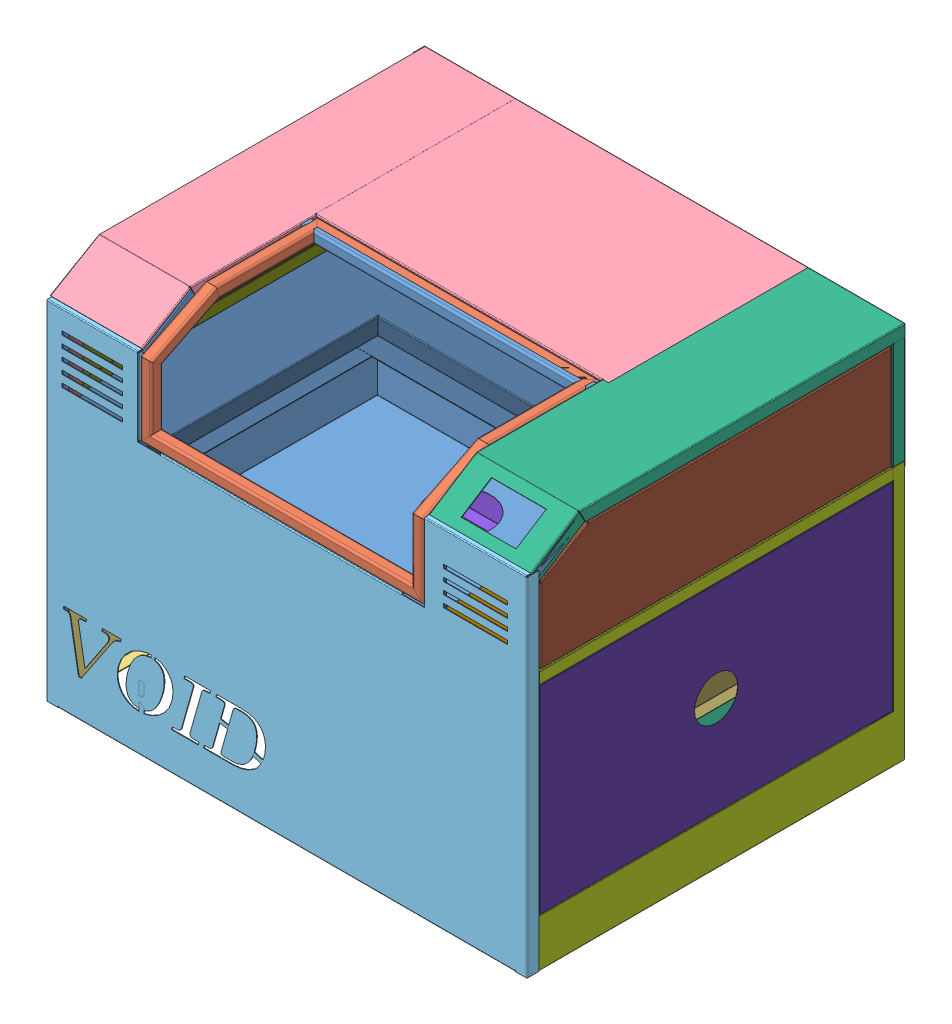
SolidWorks assembly Assem2222, configuration Default. Lengths in mm.
Overall size (1273.78 1001.74 1003.47).
19 component instances, 19 part files, 54 mates.
Components (placement in the parent):
- fram laser1-1: fram laser1 [Default<As Machined>] at (760.0871 624.0307 1171.9426) size (1270 1000 1000)
- door laser2-1: door laser2 [Default<As Machined>] at (485.0871 1026.2791 1646.4121) x (0 0 -1) z (1 0 0) size (469.25 283 750)
- left side-1: left side [Default] at (-496.6495 621.9791 1182.8381) x (-1 0 0) z (0 0 -1) size (33.67 1001.7 1000)
- top laft-1: top laft [Default] at (-361.5167 1123.0157 1366.189) x (0 0 1) z (-1 0 0) size (994.1 108.19 1015)
- Front-1: Front [Default] at (57.9882 671.4556 1683.7747) size (1271.74 921.74 63.67)
- top right-1: top right [Default] at (589.4697 1123.0157 1274.7007) size (303.67 330 991.42)
- right bottom-1: right bottom [Default] at (775.8237 175.3657 1106.8981) size (31.67 686.47 970.04)
- back-1: back [Default] at (140.3562 470.6811 681.3015) x (-1 0 0) z (0 0 -1) size (1270 968.4 31.67)
- bottom right-1: bottom right [Default] at (640.3581 808.0157 1182.5381) size (291.44 45.47 959)
- bottom laft-1: bottom laft [Default] at (276.9901 808.0157 949.0015) size (994 45.47 959)
- door right top-1: door right top [Default] at (776.8237 962.1398 1135.8944) size (30.3 274.04 929.65)
- control hoder-1: control hoder [Default] at (506.8237 511.2791 1182.0381) size (30 528 939.17)
- laft stand door-1: laft stand door [Default] at (-496.6495 923.3416 1667.1542) x (-1 0 0) z (0 0 -1) size (33.67 234 62.15)
- right door stand-1: right door stand [Default] at (-496.6495 1091.0791 1087.153) x (-1 0 0) z (0 0 -1) size (33.84 118 961.37)
- bottom2 right-1: bottom2 right [Default] at (645.0871 248.0157 1212.0381) size (249.7 1.74 979)
- door laft-1: door laft [Default] at (-494.9129 961.2458 1135.881) size (30.15 273.74 929.5)
- door right bottom-1: door right bottom [Default] at (775.8237 511.9157 1181.4381) size (30 526.4 935.9)
- door back-1: door back [Default] at (19.1371 948.8791 681.3015) x (-1 0 0) z (0 0 -1) size (965 279 30)
- smok collection-1: smok collection [Default] at (125.0871 627.0157 1350.7564) size (818.53 150 663.53)
Mates (geometry in assembly coordinates):
- Coincident1: coincident aligned: plane of fram laser1-1 through (-269.9129 1121.2791 1246.8381) normal (0 1 0); plane of door laser2-1 through (485.0871 1121.2791 1237.5929) normal (0 1 0)
- Coincident2: coincident aligned: plane of fram laser1-1 through (-269.9129 801.0791 1682.0381) normal (0 0 1); plane of door laser2-1 through (485.0871 863.0791 1682.0381) normal (0 0 1)
- Width1: width anti-aligned: plane of door laser2-1 through (500.0871 1096.4791 1505.7929) normal (1 0 0); plane of door laser2-1 through (-249.9129 1116.0791 1505.7929) normal (-1 0 0); plane of fram laser1-1 through (-254.9129 1116.0791 1547.0381) normal (1 0 0); plane of fram laser1-1 through (505.0871 1096.4791 1547.0381) normal (-1 0 0)
- Coincident8: coincident anti-aligned: plane of fram laser1-1 through (-479.9129 1096.4791 682.0381) normal (0 0 -1); plane of top laft-1 through (-361.5167 1123.0157 682.0381) normal (0 0 1)
- Coincident12: coincident aligned: plane of fram laser1-1 through (-470.1129 121.2791 706.8381) normal (0 -1 0); plane of left side-1 through (-496.6495 121.2791 1182.8381) normal (0 -1 0)
- Coincident13: coincident anti-aligned: plane of fram laser1-1 through (-269.9129 801.0791 1682.0381) normal (0 0 1); plane of Front-1 through (57.9882 671.4556 1682.0381) normal (0 0 -1)
- Coincident14: coincident anti-aligned: plane of fram laser1-1 through (520.0871 1041.2791 1676.8381) normal (0 1 0); plane of Front-1 through (57.9882 1041.2791 1683.7747) normal (0 -1 0)
- Coincident15: coincident anti-aligned: plane of fram laser1-1 through (775.0871 121.2791 1657.2381) normal (1 0 0); plane of Front-1 through (775.0871 671.4556 1683.7747) normal (-1 0 0)
- Coincident17: coincident anti-aligned: plane of top laft-1 through (520.0871 1121.2791 1210.7881) normal (1 0 0); plane of top right-1 through (520.0871 1121.2791 1210.7881) normal (-1 0 0)
- Coincident18: coincident anti-aligned: plane of fram laser1-1 through (750.2871 1106.2791 682.0381) normal (0 0 -1); plane of top right-1 through (589.4697 1123.0157 682.0381) normal (0 0 1)
- Coincident19: coincident anti-aligned: plane of fram laser1-1 through (-494.9129 121.2791 1676.8381) normal (-1 0 0); plane of left side-1 through (-494.9129 621.9791 1182.8381) normal (1 0 0)
- Coincident20: coincident anti-aligned: plane of fram laser1-1 through (-479.9129 1121.2791 706.8381) normal (0 1 0); plane of top right-1 through (589.4697 1121.2791 1274.7007) normal (0 -1 0)
- Coincident21: coincident anti-aligned: plane of fram laser1-1 through (775.0871 801.0791 1667.0381) normal (1 0 0); plane of right bottom-1 through (775.0871 175.3657 1106.8981) normal (-1 0 0)
- Coincident22: coincident aligned: plane of fram laser1-1 through (750.2871 1106.2791 682.0381) normal (0 0 -1); plane of right bottom-1 through (775.0871 122.0157 682.0381) normal (0 0 -1)
- Coincident23: coincident aligned: plane of fram laser1-1 through (769.8871 121.2791 706.8381) normal (0 -1 0); plane of right bottom-1 through (775.8237 121.2791 1106.8981) normal (0 -1 0)
- Coincident25: coincident anti-aligned: plane of fram laser1-1 through (-489.7129 1106.2791 682.0381) normal (0 0 -1); plane of back-1 through (140.3562 470.6811 682.0381) normal (0 0 1)
- Coincident26: coincident anti-aligned: plane of top right-1 through (525.0871 1121.2791 680.3015) normal (-1 0 0); plane of back-1 through (525.0871 792.6791 682.0381) normal (1 0 0)
- Coincident27: coincident anti-aligned: plane of fram laser1-1 through (529.8871 806.2791 1667.0381) normal (0 1 0); plane of bottom right-1 through (640.3581 806.2791 1182.5381) normal (0 -1 0)
- Coincident28: coincident anti-aligned: plane of fram laser1-1 through (529.8871 791.2791 1652.0381) normal (0 0 -1); plane of bottom right-1 through (520.0871 806.2791 1652.0381) normal (0 0 1)
- Coincident29: coincident anti-aligned: plane of fram laser1-1 through (505.0871 781.4791 1667.0381) normal (-1 0 0); plane of bottom right-1 through (505.0871 808.0157 1182.5381) normal (1 0 0)
- Coincident30: coincident anti-aligned: plane of fram laser1-1 through (-260.1129 791.2791 1652.0381) normal (0 0 -1); plane of bottom laft-1 through (-254.9129 806.2791 1652.0381) normal (0 0 1)
- Coincident31: coincident anti-aligned: plane of fram laser1-1 through (-260.1129 806.2791 1667.0381) normal (0 1 0); plane of bottom laft-1 through (276.9901 806.2791 949.0015) normal (0 -1 0)
- Coincident32: coincident anti-aligned: plane of fram laser1-1 through (-254.9129 801.0791 1667.0381) normal (1 0 0); plane of bottom laft-1 through (-254.9129 808.0157 949.0015) normal (-1 0 0)
- Coincident36: coincident anti-aligned: plane of fram laser1-1 through (-494.9129 121.2791 1676.8381) normal (-1 0 0); plane of laft stand door-1 through (-494.9129 923.3416 1667.1542) normal (1 0 0)
- Coincident37: coincident anti-aligned: plane of fram laser1-1 through (-470.1129 121.2791 1652.0381) normal (0 0 -1); plane of laft stand door-1 through (-496.6495 923.3416 1652.0381) normal (0 0 1)
- Coincident38: coincident anti-aligned: plane of left side-1 through (-494.9129 806.2791 711.9381) normal (0 1 0); plane of laft stand door-1 through (-494.9129 806.2791 1652.0381) normal (0 -1 0)
- Coincident40: coincident anti-aligned: plane of left side-1 through (-494.9129 1122.9791 711.9381) normal (0 0 1); plane of right door stand-1 through (-462.9763 1087.3425 711.9381) normal (0 0 -1)
- Coincident41: coincident: line of top laft-1 through (-494.9129 1121.2791 682.7747) axis (0 0 1); plane of right door stand-1 through (-494.9129 1121.2791 711.9381) normal (0 1 0)
- Coincident44: coincident anti-aligned: plane of fram laser1-1 through (-489.7129 1121.2791 1540.1523) normal (0 1 0); plane of top laft-1 through (-361.5167 1121.2791 1366.189) normal (0 -1 0)
- Coincident45: coincident aligned: plane of fram laser1-1 through (-494.9129 1116.0791 1540.1523) normal (-1 0 0); plane of top laft-1 through (-494.9129 1121.2791 682.0381) normal (-1 0 0)
- Coincident46: coincident anti-aligned: plane of fram laser1-1 through (-494.9129 1116.0791 1540.1523) normal (-1 0 0); plane of right door stand-1 through (-494.9129 1091.0791 1087.153) normal (1 0 0)
- Width2: width anti-aligned: plane of control hoder-1 through (506.8237 511.2791 712.4515) normal (0 0 -1); plane of control hoder-1 through (506.8237 511.2791 1651.6247) normal (0 0 1); plane of fram laser1-1 through (510.2871 231.2791 712.0381) normal (0 0 1); plane of fram laser1-1 through (529.8871 121.2791 1652.0381) normal (0 0 -1)
- Width3: width aligned: plane of control hoder-1 through (506.8237 775.2791 1182.0381) normal (0 1 0); plane of control hoder-1 through (506.8237 247.2791 1182.0381) normal (0 -1 0); plane of fram laser1-1 through (520.0871 246.2791 687.2381) normal (0 1 0); plane of fram laser1-1 through (510.2871 776.2791 1667.0381) normal (0 -1 0)
- Coincident48: coincident aligned: plane of fram laser1-1 through (505.0871 781.4791 1667.0381) normal (-1 0 0); plane of control hoder-1 through (505.0871 511.2791 1182.0381) normal (-1 0 0)
- Width4: width aligned: plane of door right top-1 through (776.8237 962.1398 1646.7881) normal (0 0 1); plane of door right top-1 through (776.8237 962.1398 717.2881) normal (0 0 -1); plane of top right-1 through (589.4697 1123.0157 713.9747) normal (0 0 1); plane of Front-1 through (57.9882 671.4556 1650.1015) normal (0 0 -1)
- Width5: width aligned: plane of door right top-1 through (776.8237 1085.4474 1135.8944) normal (0 1 0); plane of door right top-1 through (776.8237 811.6474 1135.8944) normal (0 -1 0); plane of right bottom-1 through (775.8237 807.7523 1106.8981) normal (0 1 0); plane of top right-1 through (589.4697 1089.3425 1274.7007) normal (0 -1 0)
- Coincident49: coincident aligned: plane of top right-1 through (776.8237 1123.0157 1274.7007) normal (1 0 0); plane of door right top-1 through (776.8237 962.1398 1135.8944) normal (1 0 0)
- Coincident50: coincident anti-aligned: plane of fram laser1-1 through (529.8871 121.2791 1652.0381) normal (0 0 -1); plane of bottom2 right-1 through (505.0871 246.2791 1652.0381) normal (0 0 1)
- Coincident51: coincident anti-aligned: plane of fram laser1-1 through (535.0871 121.2791 1657.2381) normal (1 0 0); plane of bottom2 right-1 through (535.0871 246.2791 1652.0381) normal (-1 0 0)
- Coincident52: coincident anti-aligned: plane of fram laser1-1 through (520.0871 246.2791 687.2381) normal (0 1 0); plane of bottom2 right-1 through (645.0871 246.2791 1212.0381) normal (0 -1 0)
- Coincident55: coincident anti-aligned: plane of fram laser1-1 through (-470.1129 1106.2791 712.0381) normal (0 0 1); plane of left side-1 through (-466.6495 121.2791 712.0381) normal (0 0 -1)
- Width6: width anti-aligned: plane of door laft-1 through (-494.9129 961.2458 1646.7381) normal (0 0 1); plane of door laft-1 through (-494.9129 961.2458 717.2381) normal (0 0 -1); plane of laft stand door-1 through (-496.6495 923.3416 1650.3015) normal (0 0 -1); plane of left side-1 through (-496.6495 621.9791 713.6747) normal (0 0 1)
- Width7: width aligned: plane of door laft-1 through (-494.9129 1084.4291 1135.881) normal (0 1 0); plane of door laft-1 through (-494.9129 810.9291 1135.881) normal (0 -1 0); plane of left side-1 through (-496.6495 808.0157 1182.8381) normal (0 1 0); plane of right door stand-1 through (-496.6495 1087.3425 1087.153) normal (0 -1 0)
- Coincident56: coincident aligned: plane of right door stand-1 through (-496.6495 1091.0791 1087.153) normal (-1 0 0); plane of door laft-1 through (-496.6495 961.2458 1135.881) normal (-1 0 0)
- Width8: width anti-aligned: plane of door right bottom-1 through (775.8237 775.1157 1181.4381) normal (0 1 0); plane of door right bottom-1 through (775.8237 248.7157 1181.4381) normal (0 -1 0); plane of right bottom-1 through (775.8237 776.0791 1106.8981) normal (0 -1 0); plane of right bottom-1 through (775.8237 247.7523 1106.8981) normal (0 1 0)
- Width9: width anti-aligned: plane of door right bottom-1 through (775.8237 511.9157 713.4881) normal (0 0 -1); plane of door right bottom-1 through (775.8237 511.9157 1649.3881) normal (0 0 1); plane of right bottom-1 through (775.8237 175.3657 712.7747) normal (0 0 1); plane of Front-1 through (57.9882 671.4556 1650.1015) normal (0 0 -1)
- Coincident57: coincident aligned: plane of right bottom-1 through (775.8237 175.3657 1106.8981) normal (1 0 0); plane of door right bottom-1 through (775.8237 511.9157 1181.4381) normal (1 0 0)
- Coincident58: coincident aligned: plane of back-1 through (140.3562 470.6811 681.3015) normal (0 0 -1); plane of door back-1 through (19.1371 948.8791 681.3015) normal (0 0 -1)
- Width10: width aligned: plane of door back-1 through (19.1371 1088.3791 681.3015) normal (0 1 0); plane of door back-1 through (19.1371 809.3791 681.3015) normal (0 -1 0); plane of back-1 through (140.3562 808.4157 681.3015) normal (0 1 0); plane of top laft-1 through (-361.5167 1089.3425 1366.189) normal (0 -1 0)
- Coincident59: coincident anti-aligned: plane of top laft-1 through (-494.9129 1091.0791 680.3015) normal (0 -1 0); plane of back-1 through (-494.9129 1091.0791 682.0381) normal (0 1 0)
- Width12: width anti-aligned: plane of door back-1 through (-463.3629 948.8791 681.3015) normal (-1 0 0); plane of door back-1 through (501.6371 948.8791 681.3015) normal (1 0 0); plane of back-1 through (-464.0763 470.6811 681.3015) normal (1 0 0); plane of back-1 through (502.3505 470.6811 681.3015) normal (-1 0 0)
- Width13: width anti-aligned: plane of smok collection-1 through (505.0871 627.0157 1350.7564) normal (1 0 0); plane of smok collection-1 through (-254.9129 627.0157 1350.7564) normal (-1 0 0); plane of fram laser1-1 through (505.0871 781.4791 1667.0381) normal (-1 0 0); plane of fram laser1-1 through (-254.9129 801.0791 1667.0381) normal (1 0 0)
- Width14: width anti-aligned: plane of smok collection-1 through (125.0871 627.0157 1653.2564) normal (0 0 1); plane of smok collection-1 through (125.0871 627.0157 1048.2564) normal (0 0 -1); plane of fram laser1-1 through (-269.9129 781.4791 1652.0381) normal (0 0 -1); plane of bottom laft-1 through (276.9901 808.0157 1049.4747) normal (0 0 1)
- Coincident60: coincident anti-aligned: plane of fram laser1-1 through (-279.7129 776.2791 1667.0381) normal (0 -1 0); plane of smok collection-1 through (125.0871 776.2791 1350.7564) normal (0 1 0)
